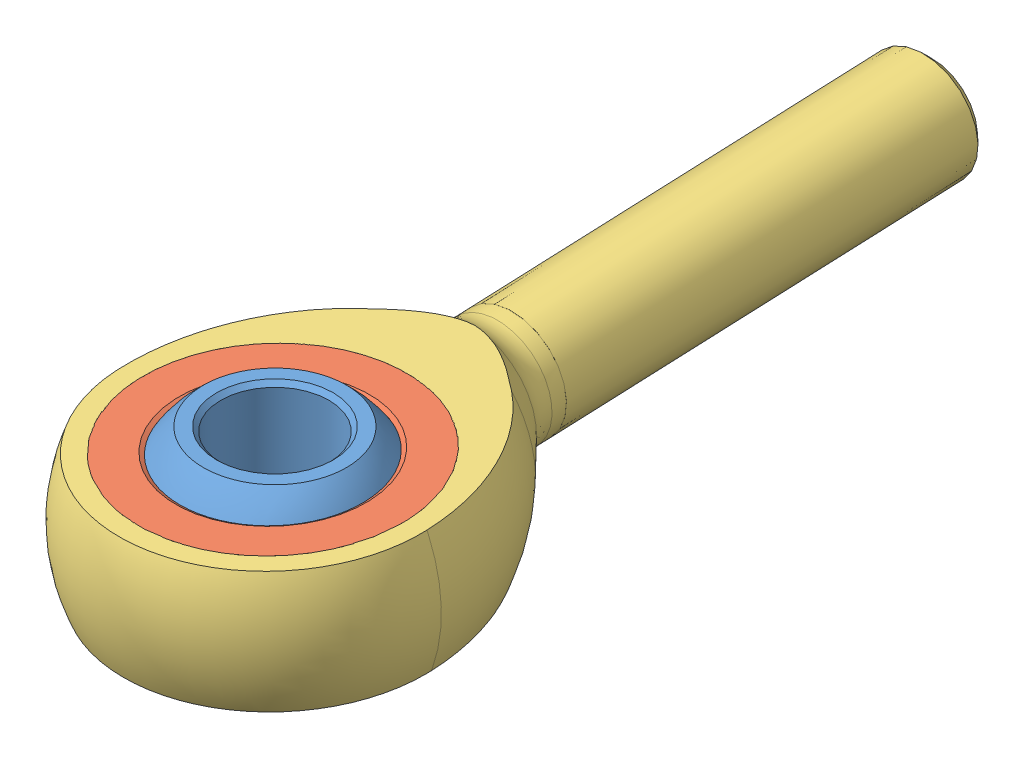
SolidWorks assembly MM-4T Rod End, configuration Default. Lengths in mm.
Overall size (21.2 20.13 49.97).
3 component instances, 3 part files, 4 mates.
Components (placement in the parent):
- MM-4T Ball-1: MM-4T Ball [Default] at origin size (12.7 12.7 12.7)
- MM-4T Sleeve-1: MM-4T Sleeve [Default] at (-1.0904 0.5261 0.0185) x (0.999384 0.022203 -0.027186) z (0.027485 -0.013262 0.999534) size (15.44 7.14 15.44)
- MM-4T Housing-1: MM-4T Housing [Default] at (-1.0904 0.5261 0.0185) x (0.999384 0.022203 -0.027186) z (0.027485 -0.013262 0.999534) size (19.45 19.05 49.2)
Mates (geometry in assembly coordinates):
- Concentric1: concentric anti-aligned: cylinder of MM-4T Housing-1 through (0 0 39.6748) axis (0.021832 -0.999666 -0.013864) radius 7.3406; cylinder of MM-4T Sleeve-1 through (0 0 39.6748) axis (-0.021832 0.999666 0.013864) radius 7.3406
- Coincident1: coincident: point of MM-4T Housing-1; point of MM-4T Sleeve-1
- Coincident8: coincident: point of MM-4T Ball-1; point of MM-4T Sleeve-1
- Coincident10: coordinate: point of MM-4T Ball-1; point of assembly
